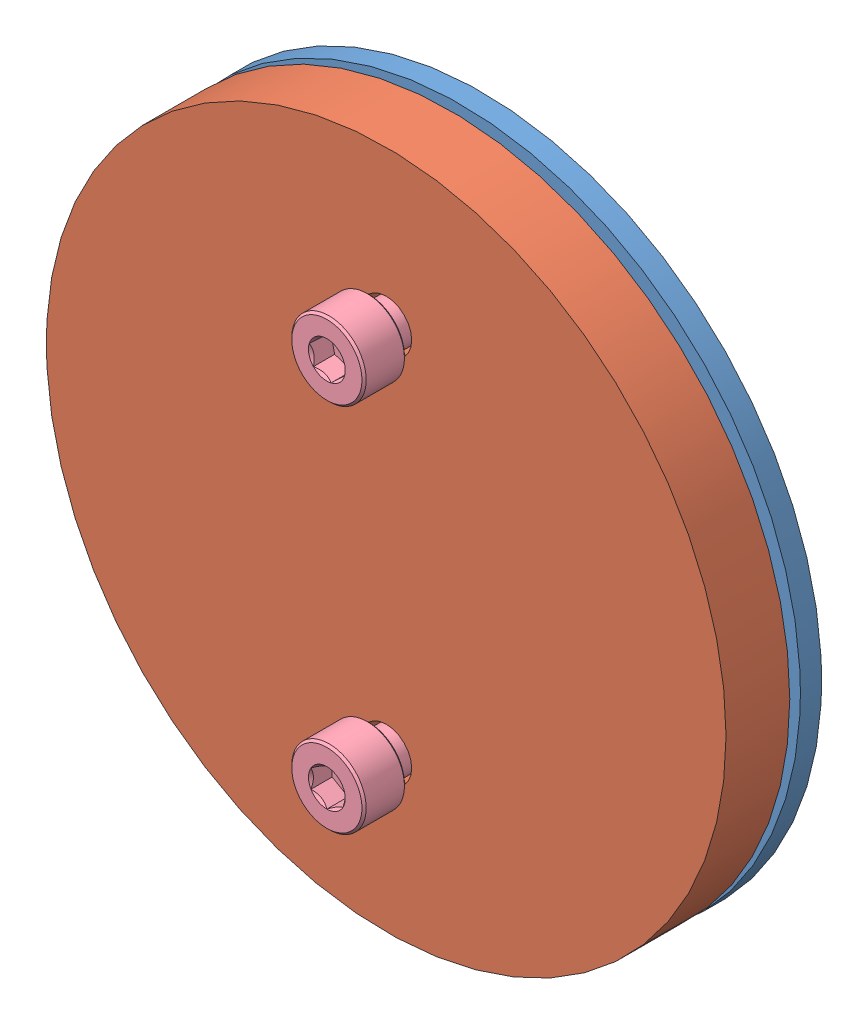
SolidWorks assembly EL-A0105-AA-TSAL Assembly1, configuration Default. Lengths in mm.
Overall size (64 64 34.98).
7 component instances, 5 part files, 11 mates.
Components (placement in the parent):
- EL-50071-AA-TSAL Bottom Housing1-1: EL-50071-AA-TSAL Bottom Housing1 [Default] at (31.8158 48.3259 30.7086) size (64 64 7)
- EL-50070-AA-TSAL Top Housing1-1: EL-50070-AA-TSAL Top Housing1 [Default] at (31.8158 48.3259 37.7086) x (-1 0 0) z (0 0 -1) size (64 64 6)
- FS-Heat Set Insert, M4x7-4.7 (94180A351)-1: FS-Heat Set Insert, M4x7-4.7 (94180A351) [94180A351] at (31.8158 65.7757 34.3586) x (0.903343 0.428919 0) z (0 0 1) size (6.35 6.35 4.7)
- BR-Black Oxide C12.9 SHCS, M4x0.7-8 (91290A140)1-1: BR-Black Oxide C12.9 SHCS, M4x0.7-8 (91290A140)1 [91290A140] at (31.8158 30.8761 38.2961) size (7 7 12.17)
- BR-Black Oxide C12.9 SHCS, M4x0.7-8 (91290A140)1-2: BR-Black Oxide C12.9 SHCS, M4x0.7-8 (91290A140)1 [91290A140] at (31.8158 65.7761 38.2961) x (0.974093 0.226149 0) z (0 0 1) size (7 7 12.17)
- FS-Heat Set Insert, M4x7-4.7 (94180A351)-2: FS-Heat Set Insert, M4x7-4.7 (94180A351) [94180A351] at (31.8158 30.8761 34.3586) x (0.999993 0.003625 0) z (0 0 1) size (6.35 6.35 4.7)
- EL-30072-AA-TSAL Mounting Tab1-2: EL-30072-AA-TSAL Mounting Tab1 [Default] at (60.8908 48.3261 73.3161) x (0 -1 0) z (0 0 -1) size (64 64 25.98)
Mates (geometry in assembly coordinates):
- Concentric1: concentric anti-aligned: cone of EL-500XX-AA-TSAL Bottom Housing-1 through (31.8158 30.8761 36.7086) axis (0 0 -1); cylinder of EL-50070-AA-TSAL Top Housing-1 through (31.8158 30.8761 38.7086) axis (0 0 1) radius 2.4
- Concentric2: concentric anti-aligned: cone of EL-500XX-AA-TSAL Bottom Housing-1 through (31.8158 65.7757 36.7086) axis (0 0 -1); cylinder of EL-50070-AA-TSAL Top Housing-1 through (31.8158 65.7757 38.7086) axis (0 0 1) radius 2.4
- Concentric3: concentric anti-aligned: cylinder of EL-500XX-AA-TSAL Bottom Housing-1 through (31.8158 48.3259 36.7086) axis (0 0 -1) radius 30; cylinder of EL-50070-AA-TSAL Top Housing-1 through (31.8158 48.3259 32.7086) axis (0 0 1) radius 30.05
- Coincident1: coincident aligned: plane of EL-500XX-AA-TSAL Bottom Housing-1 through (31.8158 48.3259 36.7086) normal (0 0 1); circle of EL-500XX-AA-TSAL Top Housing-1
- Concentric7: concentric anti-aligned: cone of EL-50071-AA-TSAL Bottom Housing-1 through (31.8158 65.7757 36.7086) axis (0 0 -1); cylinder of FS-Heat Set Insert, M4x7-4.7 (94180A351)-1 through (31.8158 65.7757 36.7086) axis (0 0 1) radius 3.175
- Coincident3: coincident aligned: plane of EL-50071-AA-TSAL Bottom Housing-1 through (31.8158 48.3259 36.7086) normal (0 0 1); circle of FS-Heat Set Insert, M4x7-4.7 (94180A351)-1
- Concentric8: concentric anti-aligned: cone of EL-50071-AA-TSAL Bottom Housing-1 through (31.8158 30.8761 36.7086) axis (0 0 -1); cylinder of FS-Heat Set Insert, M4x7-4.7 (94180A351)-2 through (31.8158 30.8761 36.7086) axis (0 0 1) radius 3.175
- Coincident4: coincident aligned: plane of EL-50071-AA-TSAL Bottom Housing-1 through (31.8158 48.3259 36.7086) normal (0 0 1); circle of FS-Heat Set Insert, M4x7-4.7 (94180A351)-2
- Concentric9: concentric aligned: cylinder of EL-50070-AA-TSAL Top Housing-1 through (31.8158 65.7757 38.7086) axis (0 0 1) radius 2.4; cylinder of EL-30072-BA-TSAL Mounting Tab-1 through (31.8158 65.7761 40.2961) axis (0 0 1) radius 2.25
- Concentric10: concentric aligned: cylinder of EL-50070-AA-TSAL Top Housing-1 through (31.8158 30.8761 38.7086) axis (0 0 1) radius 2.4; cylinder of EL-30072-BA-TSAL Mounting Tab-1 through (31.8158 30.8761 40.2961) axis (0 0 1) radius 2.25
- Coincident5: coincident anti-aligned: plane of EL-50070-AA-TSAL Top Housing-1 through (31.8158 48.3259 38.7086) normal (0 0 1); plane of EL-30072-BA-TSAL Mounting Tab-1 through (60.8908 48.3261 38.7086) normal (0 0 -1)
